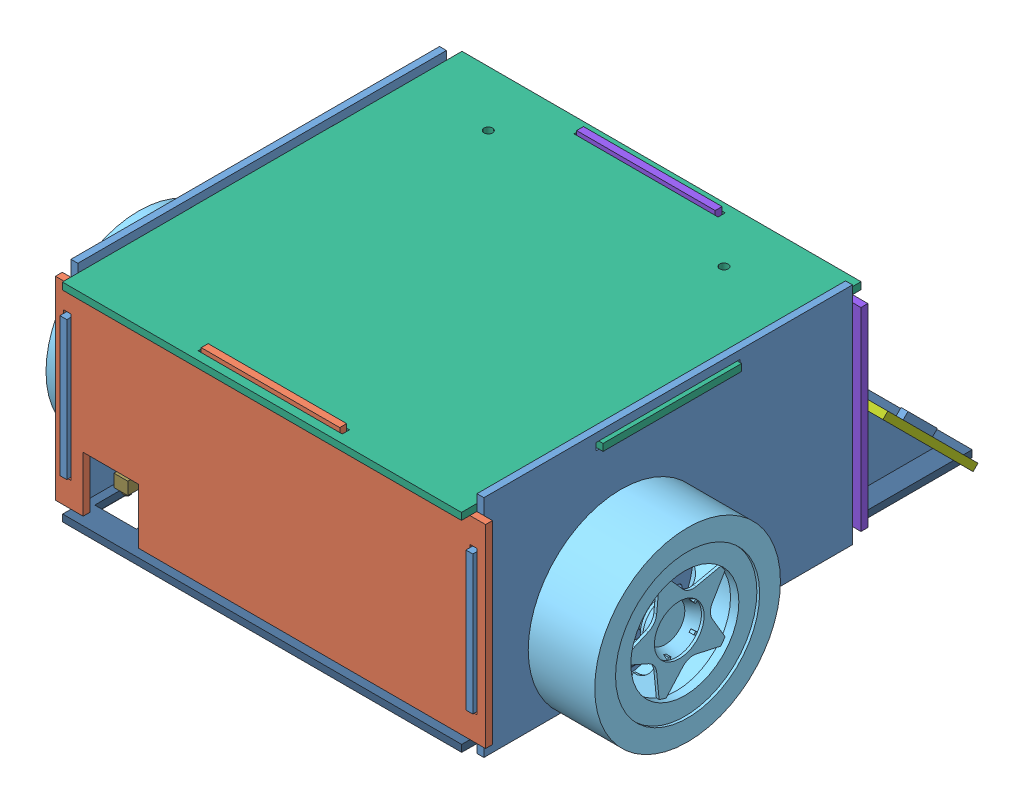
SolidWorks assembly prototype IR with PCB, configuration Default. Lengths in mm.
Overall size (198 88.6 184.3).
20 component instances, 13 part files, 55 mates.
Components (placement in the parent):
- side-1: side [Default] at (115.9411 112.7151 82.8714) x (0 -1 0) z (0 0 1) size (81.2 2.5 167.64)
- back-1: back [Default] at (190.4411 112.7151 151.8714) x (0 1 0) z (-1 0 0) size (78 2.5 155.2)
- side-2: side [Default] at (262.4411 112.7151 82.8714) x (0 -1 0) z (0 0 1) size (81.2 2.5 167.64)
- battery holder-1: battery holder [Default] at (190.4411 77.7151 83.5763) size (75 20 41)
- motor-1: motor [Default] at (137.4411 98.2151 92.8714) x (0 0 1) z (-1 0 0) size (67.5 22 35)
- wheel-1: wheel [Default] at (95.4411 98.2151 100.3714) x (0 -1 0) z (0 0 -1) size (67 27 67)
- top-2: top [Default] at (190.4411 147.7651 82.8714) size (152 2.5 144.2)
- wheel-2: wheel [Default] at (285.4411 98.2151 100.3714) x (0 1 0) z (0 0 -1) size (67 27 67)
- motor-2: motor [Default] at (243.4411 98.2151 92.8714) x (0 0 1) z (1 0 0) size (67.5 22 35)
- defender-1: defender [Default] at (190.4411 94.9118 -5.4319) x (1 0 0) z (0 0.707107 0.707107) size (159.2 2.5 46)
- front-1: front [Default] at (190.3911 112.7651 16.3714) x (-1 0 0) z (0 -1 0) size (155.2 2.5 78)
- ultrasonic sensor-1: ultrasonic sensor [Default] at (190.3911 125.5833 18.3714) x (1 0 0) z (0 1 0) size (45 12 20)
- bottom2-1: bottom2 [Default] at (190.4411 75.2151 82.7714) size (152 2.5 184.2)
- PCB-1: PCB [Default] at (190.4411 107.7151 88.0697) size (53 10 80)
- IR sensor-7: IR sensor [Default] at (136.1426 94.2151 35.7404) x (0.601378 0 0.798965) z (0.798965 0 -0.601378) size (35.68 17.11 13.5)
- IR sensor-8: IR sensor [Default] at (140.4409 94.2151 138.8525) x (1 0 0) z (0 0 -1) size (35.68 17.11 13.5)
- IR sensor-9: IR sensor [Default] at (240.4412 94.2151 138.8525) x (-1 0 0) z (0 0 1) size (35.68 17.11 13.5)
- IR sensor-10: IR sensor [Default] at (244.7624 94.2151 35.7577) x (-0.604059 0 0.796939) z (0.796939 0 0.604059) size (35.68 17.11 13.5)
- IR sensor 2-1: IR sensor 2 [Default] at (147.9411 126.7651 22.2714) x (0 0 1) z (1 0 0) size (41.18 6.43 13.5)
- IR sensor 2-2: IR sensor 2 [Default] at (232.9411 126.7651 22.2714) x (0 0 1) z (1 0 0) size (41.18 6.43 13.5)
Mates (geometry in assembly coordinates):
- Coincident30: coincident anti-aligned: plane of motor-1 through (118.4411 92.2151 106.3714) normal (-1 0 0); plane of wheel-1 through (118.4411 98.2151 100.3714) normal (1 0 0)
- Concentric9: concentric anti-aligned: circle of motor-1; circle of wheel-1
- Coincident31: coincident anti-aligned: plane of side-1 through (118.4411 112.7151 82.8714) normal (1 0 0); plane of motor-1 through (118.4411 92.2151 106.3714) normal (-1 0 0)
- Parallel13: parallel aligned: line of motor-1 through (145.4411 100.4651 101.4611) axis (0 -1 0); line of wheel-1 through (118.4411 100.4512 102.3714) axis (0 -1 0)
- Width13: width anti-aligned: plane of top-2 through (190.4411 150.2651 82.8714) normal (0 1 0); plane of top-2 through (190.4411 147.7651 82.8714) normal (0 -1 0); plane of side-1 through (118.4411 150.3151 108.8714) normal (0 -1 0); plane of side-1 through (118.4411 147.7151 108.8714) normal (0 1 0)
- Width14: width aligned: plane of side-1 through (118.4411 150.3151 108.8714) normal (0 0 -1); plane of side-1 through (118.4411 150.3151 56.8714) normal (0 0 1); plane of top-2 through (118.4411 150.2651 57.8714) normal (0 0 -1); plane of top-2 through (114.4411 150.2651 107.8714) normal (0 0 1)
- Width15: width anti-aligned: plane of top-2 through (118.4411 150.2651 107.8714) normal (-1 0 0); plane of top-2 through (262.4411 150.2651 154.9714) normal (1 0 0); plane of back-1 through (215.4411 147.7151 149.3714) normal (1 0 0); plane of back-1 through (165.4411 147.7151 149.3714) normal (-1 0 0)
- Coincident47: coincident anti-aligned: plane of wheel-2 through (262.4411 98.2151 100.3714) normal (-1 0 0); plane of motor-2 through (262.4411 104.2151 106.3714) normal (1 0 0)
- Parallel15: parallel aligned: line of wheel-2 through (262.4411 95.979 102.3714) axis (0 1 0); line of motor-2 through (235.4411 95.9651 101.4611) axis (0 1 0)
- Coincident50: coincident anti-aligned: plane of side-2 through (262.4411 112.7151 82.8714) normal (-1 0 0); plane of motor-2 through (262.4411 104.2151 106.3714) normal (1 0 0)
- Parallel16: parallel aligned: line of side-2 through (262.4411 153.3151 16.3714) axis (0 0 1); line of motor-2 through (243.4411 109.2151 74.3714) axis (0 0 1)
- Coincident52: coincident anti-aligned: plane of side-2 through (262.4411 147.9651 47.6214) normal (0 0.707107 -0.707107); plane of defender-1 through (190.4411 94.9118 -5.4319) normal (0 -0.707107 0.707107)
- Width20: width anti-aligned: plane of side-2 through (262.4411 54.3585 24.5148) normal (0 -0.707107 -0.707107); plane of side-2 through (262.4411 64.9651 35.1214) normal (0 0.707107 0.707107); plane of defender-1 through (265.0411 91.3763 -12.5029) normal (0 0.707107 0.707107); plane of defender-1 through (265.0411 101.9829 -1.8963) normal (0 -0.707107 -0.707107)
- Coincident53: coincident anti-aligned: plane of side-2 through (262.4411 112.7151 82.8714) normal (-1 0 0); plane of defender-1 through (262.4411 101.9829 -1.8963) normal (1 0 0)
- Coincident54: coincident anti-aligned: plane of side-1 through (118.4411 112.7151 82.8714) normal (1 0 0); plane of defender-1 through (118.4411 101.9829 -1.8963) normal (-1 0 0)
- Coincident55: coincident anti-aligned: plane of side-2 through (264.9411 137.7151 16.3714) normal (0 0 -1); plane of front-1 through (190.3911 112.7651 16.3714) normal (0 0 1)
- Coincident56: coincident anti-aligned: plane of top-2 through (190.4411 147.7651 82.8714) normal (0 -1 0); plane of front-1 through (215.3911 147.7651 13.8714) normal (0 1 0)
- Width23: width aligned: plane of side-2 through (264.9411 112.7151 82.8714) normal (1 0 0); plane of side-2 through (262.4411 112.7151 82.8714) normal (-1 0 0); plane of front-1 through (262.3911 86.7651 13.8714) normal (1 0 0); plane of front-1 through (264.9911 86.7651 13.8714) normal (-1 0 0)
- Coincident57: coincident anti-aligned: plane of front-1 through (190.3911 112.7651 16.3714) normal (0 0 1); plane of ultrasonic sensor-1 through (190.3911 125.5833 16.3714) normal (0 0 -1)
- Concentric22: concentric aligned: circle of front-1; circle of ultrasonic sensor-1
- Concentric26: concentric aligned: circle of side-2; circle of wheel-2
- Parallel19: parallel aligned: plane of side-1 through (118.4411 153.3151 16.3714) normal (0 1 0); plane of motor-1 through (118.4411 109.2151 74.3714) normal (0 1 0)
- Concentric27: concentric anti-aligned: circle of side-1; circle of wheel-1
- Coincident59: coincident anti-aligned: plane of back-1 through (268.0411 77.7151 149.3714) normal (0 -1 0); plane of bottom2-1 through (190.4411 77.7151 82.7714) normal (0 1 0)
- Coincident60: coincident anti-aligned: plane of back-1 through (190.4411 112.7151 151.8714) normal (0 0 1); plane of bottom2-1 through (190.4411 77.7151 151.8714) normal (0 0 -1)
- Coincident61: coincident anti-aligned: plane of side-1 through (118.4411 112.7151 82.8714) normal (1 0 0); plane of bottom2-1 through (118.4411 77.7151 82.7714) normal (-1 0 0)
- Width24: width anti-aligned: plane of back-1 through (165.4411 77.7151 149.3714) normal (-1 0 0); plane of bottom2-1 through (215.4411 77.7151 149.3714) normal (1 0 0); plane of back-1 through (164.4411 77.7151 82.7714) normal (1 0 0); plane of bottom2-1 through (216.4411 77.7151 82.7714) normal (-1 0 0)
- Coincident62: coincident anti-aligned: plane of back-1 through (190.4411 112.7151 149.3714) normal (0 0 -1); plane of side-2 through (264.9411 153.3151 149.3714) normal (0 0 1)
- Coincident63: coincident anti-aligned: plane of side-1 through (118.4411 77.7151 108.8714) normal (0 -1 0); plane of bottom2-1 through (190.4411 77.7151 82.7714) normal (0 1 0)
- Coincident64: coincident anti-aligned: plane of side-1 through (118.4411 137.7151 16.3714) normal (0 0 -1); plane of front-1 through (190.3911 112.7651 16.3714) normal (0 0 1)
- Concentric28: concentric aligned: circle of battery holder-1; circle of bottom2-1
- Concentric29: concentric aligned: circle of battery holder-1; circle of bottom2-1
- Coincident65: coincident anti-aligned: plane of battery holder-1 through (190.4411 77.7151 83.5763) normal (0 -1 0); plane of bottom2-1 through (190.4411 77.7151 82.7714) normal (0 1 0)
- Concentric30: concentric aligned: circle of wheel-2; circle of motor-2
- Coincident66: coincident anti-aligned: plane of side-2 through (262.4411 112.7151 82.8714) normal (-1 0 0); plane of bottom2-1 through (262.4411 77.7151 82.7714) normal (1 0 0)
- Coincident67: coincident anti-aligned: plane of side-2 through (264.9411 77.7151 108.8714) normal (0 -1 0); plane of bottom2-1 through (190.4411 77.7151 82.7714) normal (0 1 0)
- Concentric31: concentric aligned: circle of bottom2-1; circle of PCB-1
- Concentric32: concentric aligned: circle of bottom2-1; circle of PCB-1
- Distance7: distance = 30 mm anti-aligned: plane of PCB-1 through (190.4411 107.7151 88.0697) normal (0 -1 0); plane of bottom2-1 through (190.4411 77.7151 82.7714) normal (0 1 0)
- Concentric33: concentric anti-aligned: circle of bottom2-1; circle of IR sensor-7
- Distance10: distance = 15 mm anti-aligned: plane of IR sensor-7 through (136.1426 92.7151 35.7404) normal (0 -1 0); plane of bottom2-1 through (190.4411 77.7151 82.7714) normal (0 1 0)
- Concentric34: concentric anti-aligned: circle of bottom2-1; circle of IR sensor-8
- Distance11: distance = 15 mm anti-aligned: plane of IR sensor-8 through (140.4409 92.7151 138.8525) normal (0 -1 0); plane of bottom2-1 through (190.4411 77.7151 82.7714) normal (0 1 0)
- Parallel20: parallel anti-aligned: line of bottom2-1 through (118.4411 77.7151 154.8714) axis (1 0 0); line of IR sensor-8 through (155.9409 94.2151 145.6025) axis (-1 0 0)
- Concentric36: concentric aligned: circle of bottom2-1; circle of IR sensor-9
- Parallel21: parallel anti-aligned: line of bottom2-1 through (118.4411 77.7151 154.8714) axis (1 0 0); line of IR sensor-9 through (255.9412 94.2151 145.6025) axis (-1 0 0)
- Distance12: distance = 15 mm anti-aligned: plane of IR sensor-9 through (240.4412 92.7151 138.8525) normal (0 -1 0); plane of bottom2-1 through (190.4411 77.7151 82.7714) normal (0 1 0)
- Concentric37: concentric aligned: circle of bottom2-1; circle of IR sensor-10
- Distance13: distance = 15 mm anti-aligned: plane of IR sensor-10 through (244.7624 92.7151 35.7577) normal (0 -1 0); plane of bottom2-1 through (190.4411 77.7151 82.7714) normal (0 1 0)
- Concentric39: concentric aligned: circle of top-2; circle of IR sensor 2-1
- Distance15: distance = 21 mm anti-aligned: plane of top-2 through (190.4411 147.7651 82.8714) normal (0 -1 0); plane of IR sensor 2-1 through (147.9411 126.7651 22.2714) normal (0 1 0)
- Parallel23: parallel anti-aligned: line of top-2 through (118.4411 150.2651 10.7714) axis (0 0 1); line of IR sensor 2-1 through (141.1911 126.7651 37.7714) axis (0 0 -1)
- Parallel24: parallel aligned: line of side-2 through (262.4411 153.3151 16.3714) axis (0 0 1); line of IR sensor 2-2 through (239.6911 126.7651 6.7714) axis (0 0 1)
- Concentric42: concentric anti-aligned: circle of top-2; circle of IR sensor 2-2
- Distance16: distance = 21 mm anti-aligned: plane of IR sensor 2-2 through (232.9411 126.7651 22.2714) normal (0 1 0); plane of top-2 through (190.4411 147.7651 82.8714) normal (0 -1 0)
